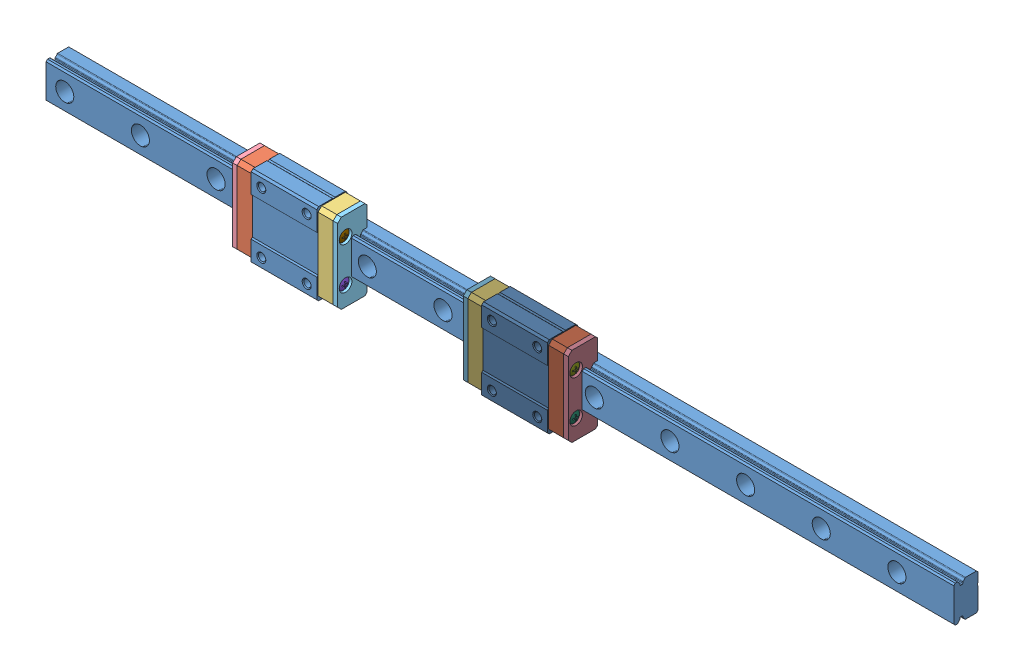
SolidWorks assembly MGN12C2R300ZFC-HiwinCorporation-3D-10-31-2020, configuration Default. Lengths in mm.
Overall size (300 27 13.07).
21 component instances, 19 part files, 4 mates.
Components (placement in the parent):
- MGN12 Carriage^MGN12C2R300ZFC-HiwinCorporation-3D-10-31-2020-1: MGN12 Carriage^MGN12C2R300ZFC-HiwinCorporation-3D-10-31-2020 [Default] at (-10.5656 0 0) size (34.9 27 10) (virtual)
  - PRODUCT_ID_1-1: PRODUCT_ID_1 [Default] at origin size (21.7 27 10)
  - PRODUCT_ID_2-1: PRODUCT_ID_2 [Default] at origin size (5 26.4 9.6)
  - PRODUCT_ID_3-1: PRODUCT_ID_3 [Default] at origin size (5 26.4 9.6)
  - PRODUCT_ID_4-1: PRODUCT_ID_4 [Default] at origin size (1.5 26.4 9.6)
  - PRODUCT_ID_5-1: PRODUCT_ID_5 [Default] at origin size (1.5 26.4 9.6)
  - PRODUCT_ID_6-1: PRODUCT_ID_6 [Default] at origin size (1.7 4 4)
  - PRODUCT_ID_7-1: PRODUCT_ID_7 [Default] at origin size (1.7 4 4)
  - PRODUCT_ID_8-1: PRODUCT_ID_8 [Default] at origin size (1.7 4 4)
  - PRODUCT_ID_9-1: PRODUCT_ID_9 [Default] at origin size (1.7 4 4)
- Assem7^MGN12C2R300ZFC-HiwinCorporation-3D-10-31-2020-1: Assem7^MGN12C2R300ZFC-HiwinCorporation-3D-10-31-2020 [Default] at (-45.9383 0 0) size (34.9 27 10) (virtual)
  - PRODUCT_ID_10-1: PRODUCT_ID_10 [Default] at origin size (21.7 27 10)
  - PRODUCT_ID_11-1: PRODUCT_ID_11 [Default] at origin size (5 26.4 9.6)
  - PRODUCT_ID_12-1: PRODUCT_ID_12 [Default] at origin size (5 26.4 9.6)
  - PRODUCT_ID_13-1: PRODUCT_ID_13 [Default] at origin size (1.5 26.4 9.6)
  - PRODUCT_ID_14-1: PRODUCT_ID_14 [Default] at origin size (1.5 26.4 9.6)
  - PRODUCT_ID_15-1: PRODUCT_ID_15 [Default] at origin size (1.7 4 4)
  - PRODUCT_ID_16-1: PRODUCT_ID_16 [Default] at origin size (1.7 4 4)
  - PRODUCT_ID_17-1: PRODUCT_ID_17 [Default] at origin size (1.7 4 4)
  - PRODUCT_ID_18-1: PRODUCT_ID_18 [Default] at origin size (1.7 4 4)
- MGN12 Rail-1: MGN12 Rail [Default] at origin size (300 12 8.07)
Mates (geometry in assembly coordinates):
- Coincident5: coincident aligned: plane of MGN12 Carriage^MGN12C2R300ZFC-HiwinCorporation-3D-10-31-2020-1 through (-10.5656 0 0) normal (0 1 0); plane of MGN12 Rail-1 through (0 0 0) normal (0 1 0)
- Coincident6: coincident aligned: plane of MGN12 Carriage^MGN12C2R300ZFC-HiwinCorporation-3D-10-31-2020-1 through (-10.5656 0 0) normal (0 0 1); plane of MGN12 Rail-1 through (0 0 0) normal (0 0 1)
- Coincident7: coincident aligned: plane of Assem7^MGN12C2R300ZFC-HiwinCorporation-3D-10-31-2020-1 through (-45.9383 0 0) normal (0 1 0); plane of MGN12 Rail-1 through (0 0 0) normal (0 1 0)
- Coincident8: coincident aligned: plane of Assem7^MGN12C2R300ZFC-HiwinCorporation-3D-10-31-2020-1 through (-45.9383 0 0) normal (0 0 1); plane of MGN12 Rail-1 through (0 0 0) normal (0 0 1)
